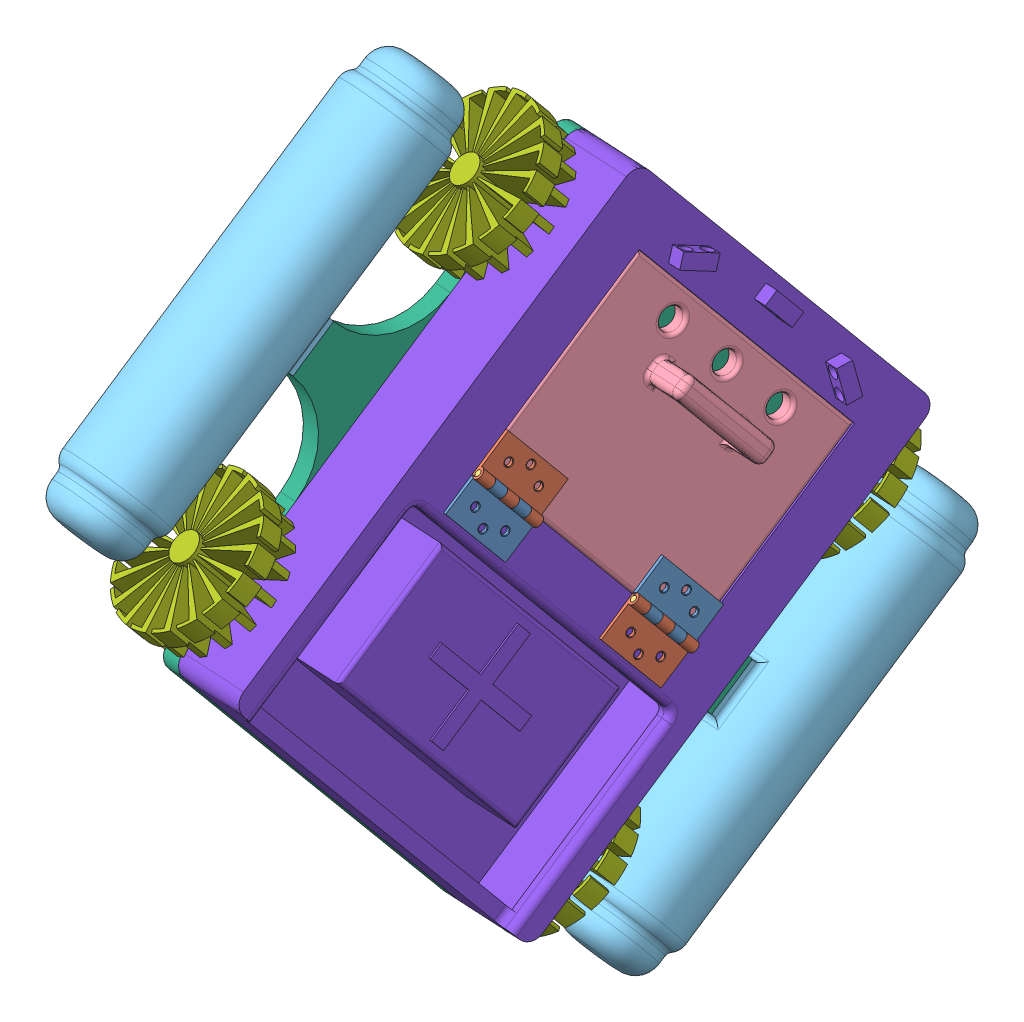
SolidWorks assembly Third assembly, configuration Default. Lengths in mm.
Overall size (580.63 1236.92 1210.33).
18 component instances, 8 part files, 10 mates.
Components (placement in the parent):
- Complete Hinge-1: Complete Hinge [Default] at (-124.8927 1333.0891 1062.4526) x (0.285346 -0.462155 -0.839637) z (-0.957155 -0.182492 -0.224836) size (133.58 137.68 15.86)
  - Hinge 1-1: Hinge 1 [Default] at (227.1069 4.4476 137.0094) x (0.923728 0.383049 0) z (0 0 1) size (100 61.24 15)
  - Hinge 2-1: Hinge 2 [Default] at (205.0971 57.5246 137.4116) x (-0.923728 -0.383049 0) z (0.005362 -0.012931 0.999902) size (100 61.24 15)
  - Hinge screw-1: Hinge screw [Default] at (158.9107 38.3721 137.4116) x (-0.005362 0.012931 -0.999902) z (-0.923728 -0.383049 0) size (8.06 8.06 100)
- Cover cap-1: Cover cap [Default] at (-225.1851 1368.8962 828.7334) x (0.282474 -0.759322 -0.586207) z (-0.957155 -0.182492 -0.224836) size (360 280 80)
- First assembly-1: First assembly [Default] at (-308.5618 570.0963 1198.9184) x (-0.282474 0.759322 0.586207) z (0.063745 0.624601 -0.778338) size (998.86 263.45 726.63)
  - Air Tank-1: Air Tank [Default] at (-63.4415 1.2515 650) size (149.43 140 600)
  - Air Tank-2: Air Tank [Default] at (795.4215 1.2515 650) x (-1 0 0) z (0 0 -1) size (149.43 140 600)
  - Base-1: Base [Default] at (165.4585 22.3484 980.1174) x (1 0 0) z (0 -1 0) size (700 700 30)
  - Wheel-1: Wheel [Default] at (80.99 7.3484 409.2812) x (0 0 1) z (-1 0 0) size (200 200 65)
  - Wheel-2: Wheel [Default] at (80.99 7.3484 893.0938) x (0 0 1) z (-1 0 0) size (200 200 65)
  - Wheel-3: Wheel [Default] at (650.99 7.3484 893.0938) x (0 0.993029 -0.117873) z (1 0 0) size (200 200 65)
  - Wheel-4: Wheel [Default] at (650.99 7.3484 409.2812) x (0 0.915955 -0.401282) z (1 0 0) size (200 200 65)
- Top cover-1: Top cover [Default] at (-204.9448 869.3614 1059.0707) x (-0.282474 0.759322 0.586207) z (0.957155 0.182492 0.224836) size (500 700 142)
- Complete Hinge-2: Complete Hinge [Default] at (-71.3617 1275.92 884.2791) x (-0.290476 0.461199 0.838402) z (-0.956169 -0.173731 -0.23571) size (133.58 137.68 15.86)
  - Hinge 1-1: Hinge 1 [Default] at (227.1069 4.4476 137.0094) x (0.923728 0.383049 0) z (0 0 1) size (100 61.24 15)
  - Hinge 2-1: Hinge 2 [Default] at (205.0971 57.5246 137.4116) x (-0.923728 -0.383049 0) z (0.005362 -0.012931 0.999902) size (100 61.24 15)
  - Hinge screw-1: Hinge screw [Default] at (158.9107 38.3721 137.4116) x (-0.005362 0.012931 -0.999902) z (-0.923728 -0.383049 0) size (8.06 8.06 100)
Mates (geometry in assembly coordinates):
- Coincidente1: coincident anti-aligned: plane of First assembly-1/Base-1 through (-271.4313 1311.9932 538.073) normal (0.957155 0.182492 0.224836); plane of Top cover-1 through (-300.6602 851.1122 1036.5871) normal (-0.957155 -0.182492 -0.224836)
- Coincidente2: coincident aligned: line of First assembly-1/Base-1 through (-261.6884 1303.5192 503.4745) axis (-0.282474 0.759322 0.586207); line of Top cover-1 through (-261.6884 1303.5192 503.4745) axis (-0.282474 0.759322 0.586207)
- Coincidente3: coincident aligned: line of First assembly-1/Base-1 through (-428.2676 1364.3208 1163.272) axis (-0.063745 -0.624601 0.778338); line of Top cover-1 through (-398.5506 1655.5019 800.4204) axis (-0.063745 -0.624601 0.778338)
- Coincidente4: coincident anti-aligned: plane of Cover cap-1 through (-202.4072 1141.1242 827.6868) normal (0.282474 -0.759322 -0.586207); plane of Top cover-1 through (-204.3216 1140.7593 827.2371) normal (-0.282474 0.759322 0.586207)
- Coincidente5: coincident anti-aligned: plane of Cover cap-1 through (-304.0977 1414.4803 1038.7212) normal (-0.063745 -0.624601 0.778338); plane of Top cover-1 through (-204.3216 1140.7593 827.2371) normal (0.063745 0.624601 -0.778338)
- Coincidente6: coincident aligned: line of Cover cap-1 through (-286.2492 1589.3685 820.7865) axis (0.282474 -0.759322 -0.586207); line of Top cover-1 through (-286.2492 1589.3685 820.7865) axis (0.282474 -0.759322 -0.586207)
- Coincidente9: coincident aligned: line of Top cover-1 through (-284.9546 1418.1301 1043.2179) axis (0.282474 -0.759322 -0.586207); line of Complete Hinge-2/Hinge 2-1 through (-273.6557 1387.7572 1019.7697) axis (0.282474 -0.759322 -0.586207)
- Coincidente10: coincident anti-aligned: line of Top cover-1 through (-267.1061 1593.0184 825.2832) axis (-0.063745 -0.624601 0.778338); line of Complete Hinge-2/Hinge 2-1 through (-284.9546 1418.1301 1043.2179) axis (0.063745 0.624601 -0.778338)
- Coincidente11: coincident anti-aligned: line of Complete Hinge-1/Hinge 1-1 through (-194.5631 1175.147 855.6318) axis (-0.282474 0.759322 0.586207); line of Top cover-1 through (-284.9546 1418.1301 1043.2179) axis (0.282474 -0.759322 -0.586207)
- Coincidente12: coincident anti-aligned: line of Complete Hinge-1/Hinge 1-1 through (-180.0769 1176.0041 793.2666) axis (-0.063745 -0.624601 0.778338); line of Top cover-1 through (-183.2641 1144.7741 832.1835) axis (0.063745 0.624601 -0.778338)
